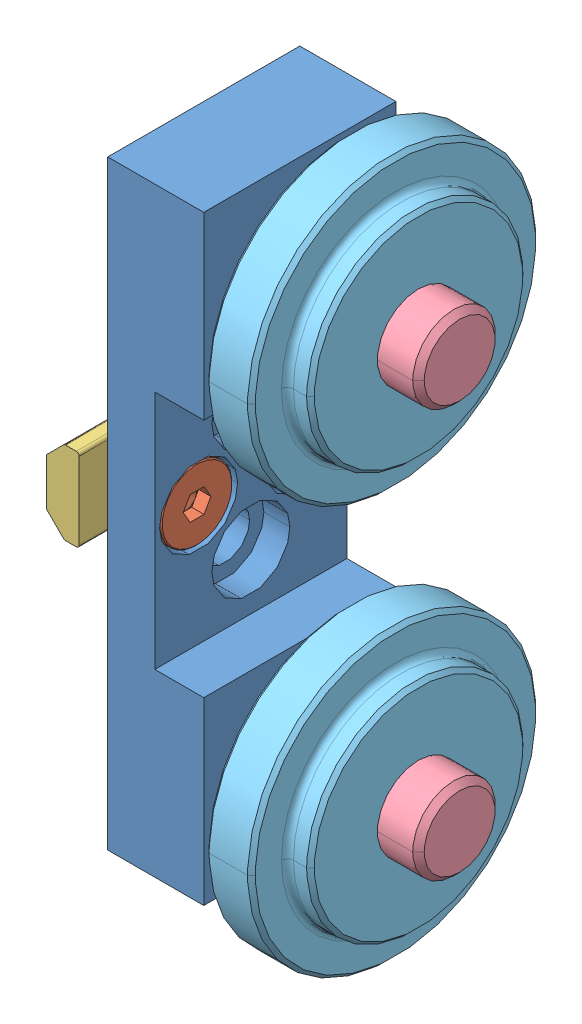
SolidWorks assembly 2018-501-A, configuration Default. Lengths in mm.
Overall size (40.56 92.08 38.1).
11 component instances, 6 part files, 0 mates.
Components (placement in the parent):
- _2750_1_b_2-1: _2750_1_b_2 [Default] at (6.223 0 0) x (0 0 -1) z (1 0 0) size (25.4 79.38 12.7)
- _2750_0_250_4-1: _2750_0_250_4 [Default] at (2.794 0 6.9088) x (-1 0 0) z (0 -1 0) size (12.75 9.53 9.53)
- _3204_6-1: _3204_6 [Default] at (-6.5532 0 6.9088) x (0 1 0) z (0 0 -1) size (10.95 4.34 12.45)
- _2750_0_250_4-2: _2750_0_250_4 [Default] at (2.794 0 -6.9088) x (-1 0 0) z (0 1 0) size (12.75 9.53 9.53)
- _3204_6-2: _3204_6 [Default] at (-6.5532 0 -6.9088) x (0 -1 0) z (0 0 1) size (10.95 4.34 12.45)
- _2281_b_10-1: _2281_b_10 [Default] at (28.3972 26.9875 0) x (-1 0 0) z (0 0 1) size (29.26 10.9 10.9)
- _2281_w_12-1: _2281_w_12 [Default] at (22.3012 26.9875 0) size (12.19 38.1 38.1)
- _2281_p2_14-1: _2281_p2_14 [Default] at (14.1986 26.9875 0) size (3 15.8 15.8)
- _2281_b_10-2: _2281_b_10 [Default] at (28.3972 -26.9875 0) x (-1 0 0) z (0 0 1) size (29.26 10.9 10.9)
- _2281_w_12-2: _2281_w_12 [Default] at (22.3012 -26.9875 0) size (12.19 38.1 38.1)
- _2281_p2_14-2: _2281_p2_14 [Default] at (14.1986 -26.9875 0) size (3 15.8 15.8)
